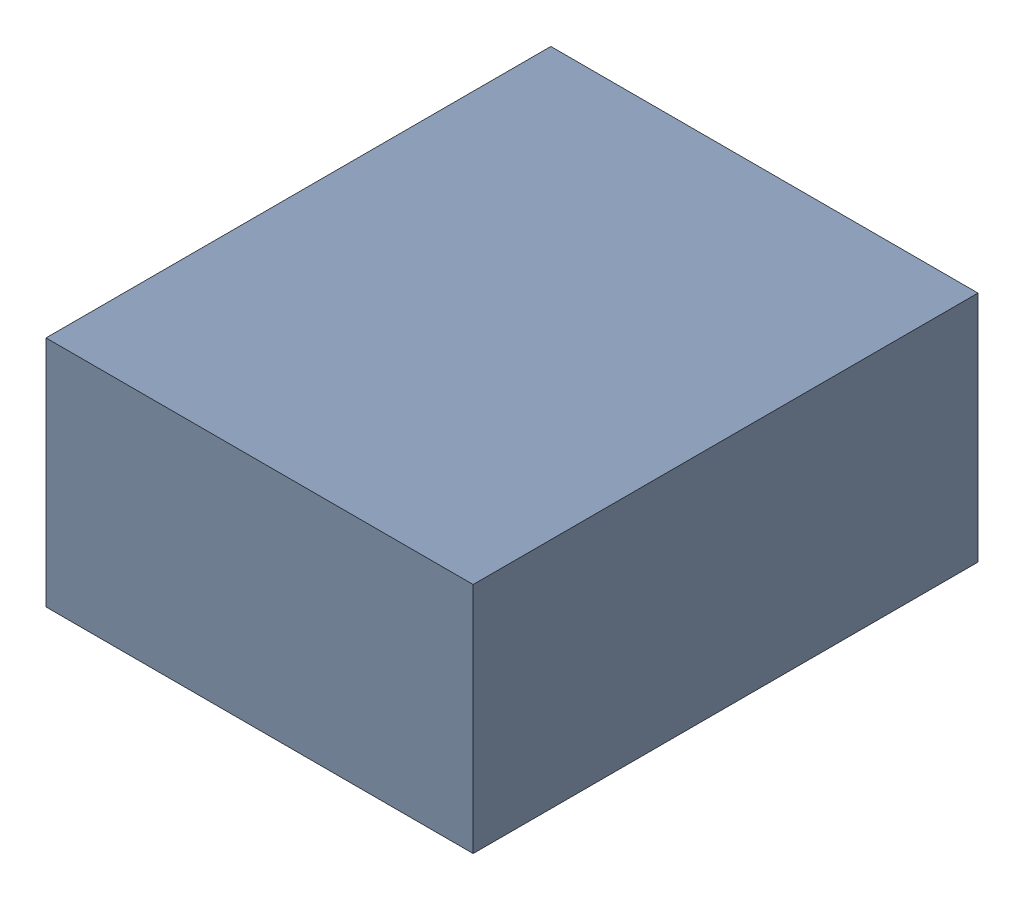
SolidWorks assembly C28_TDA1, configuration Standard. Lengths in mm.
Overall size (1.1 0.6 1.3).
2 component instances, 1 part files, 0 mates.
Components (placement in the parent):
- 885542240-1: 885542240 [Standard] at (-0.42 57.14 0) size (1.1 0.6 1.3)
  - Extruded_28-1: Extruded_28 [Standard] at origin size (1.1 0.6 1.3)
